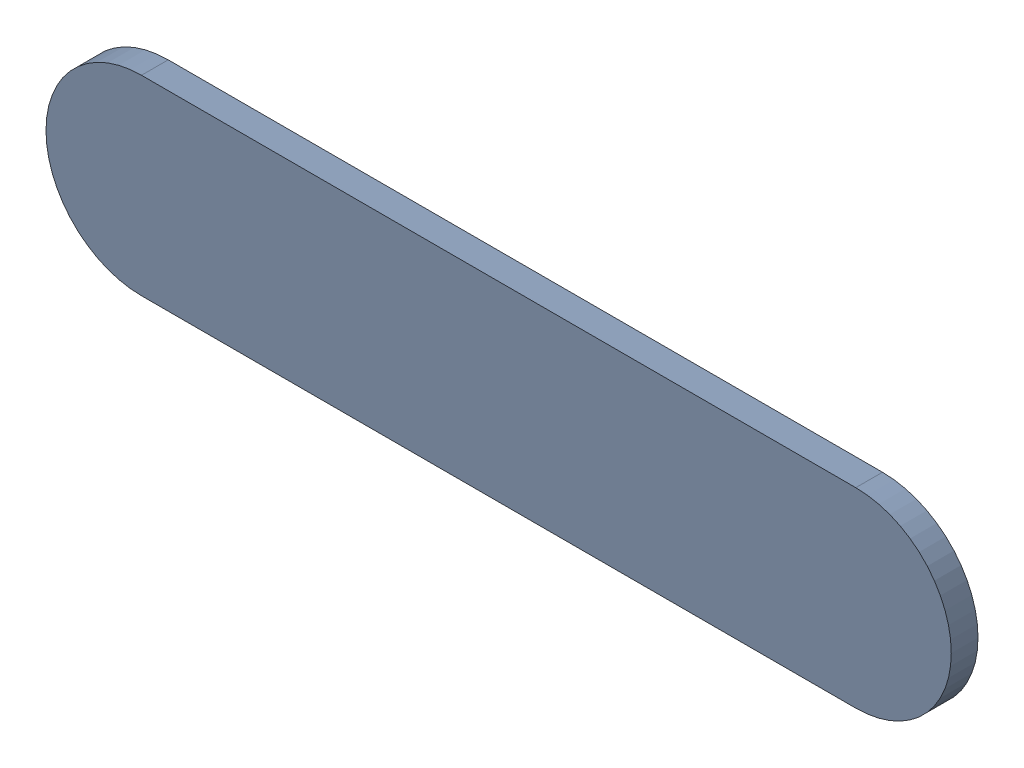
SolidWorks assembly Track (28.05mm,40mm)(29mm,40mm) on Top Layer, configuration Predeterminado. Lengths in mm.
Overall size (1.2 0.25 0.04).
2 component instances, 1 part files, 0 mates.
Components (placement in the parent):
- Track (28.05mm,40mm)(29mm,40mm) on Top Layer-1-1: Track (28.05mm,40mm)(29mm,40mm) on Top Layer-1 [Predeterminado] at (-68.317 -44.187 -0.0457) size (1.2 0.25 0.04)
  - Track (28.05mm,40mm)(29mm,40mm) on Top Layer-Part-1-1: Track (28.05mm,40mm)(29mm,40mm) on Top Layer-Part-1 [Predeterminado] at origin size (1.2 0.25 0.04)
